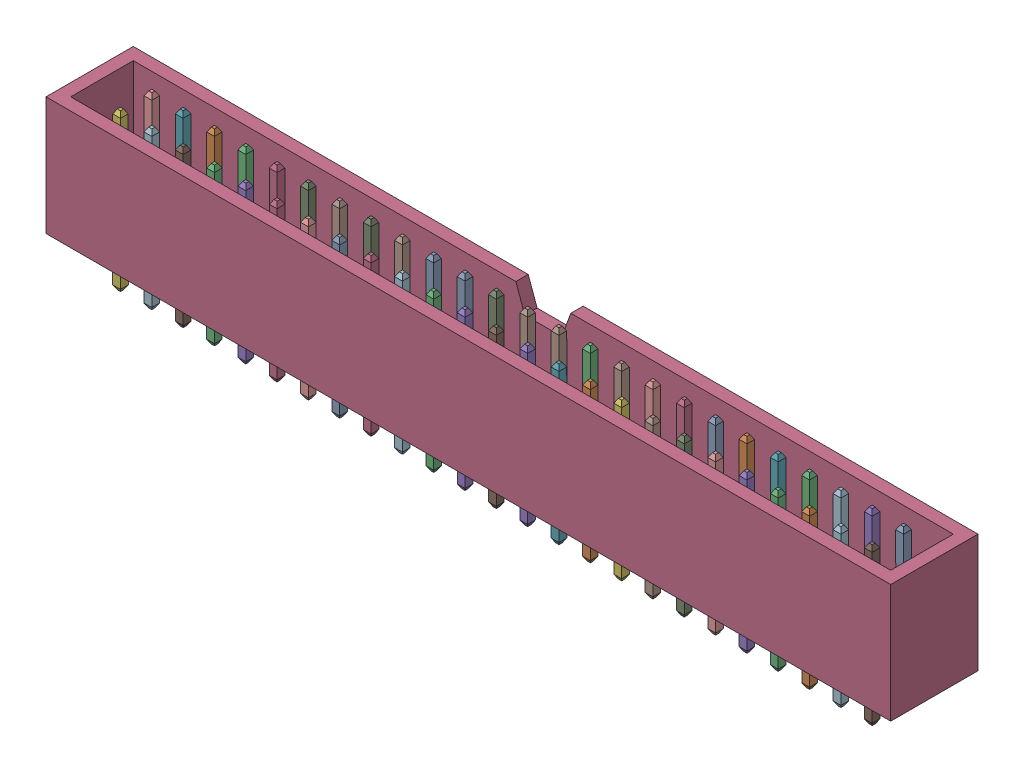
SolidWorks assembly 25 pin with case v2, configuration Default. Lengths in mm.
Overall size (68.5 12.8 7.08).
4 component instances, 3 part files, 0 mates.
Components (placement in the parent):
- Pin Header 2x15 TH Pitch 2.54mm v2-1: Pin Header 2x15 TH Pitch 2.54mm v2 [Default] at (0 0.0647 1.8778) x (1 0 0) z (0 1 0) size (38.1 5.08 12.7)
- Pin Header 2x10 TH Pitch 2.54mm v2-1: Pin Header 2x10 TH Pitch 2.54mm v2 [Default] at (38.1 0.0647 1.8778) x (1 0 0) z (0 1 0) size (25.4 5.08 12.7)
- 2X25Pin case v7-1: 2X25Pin case v7 [Default] x (1 0 0) z (0 1 0) size (68.5 7.08 9.6)
  - Component1_7-1: Component1_7 [Default] at (-1.5 -1.8778 0.0661) size (68.5 7.08 9.6)
